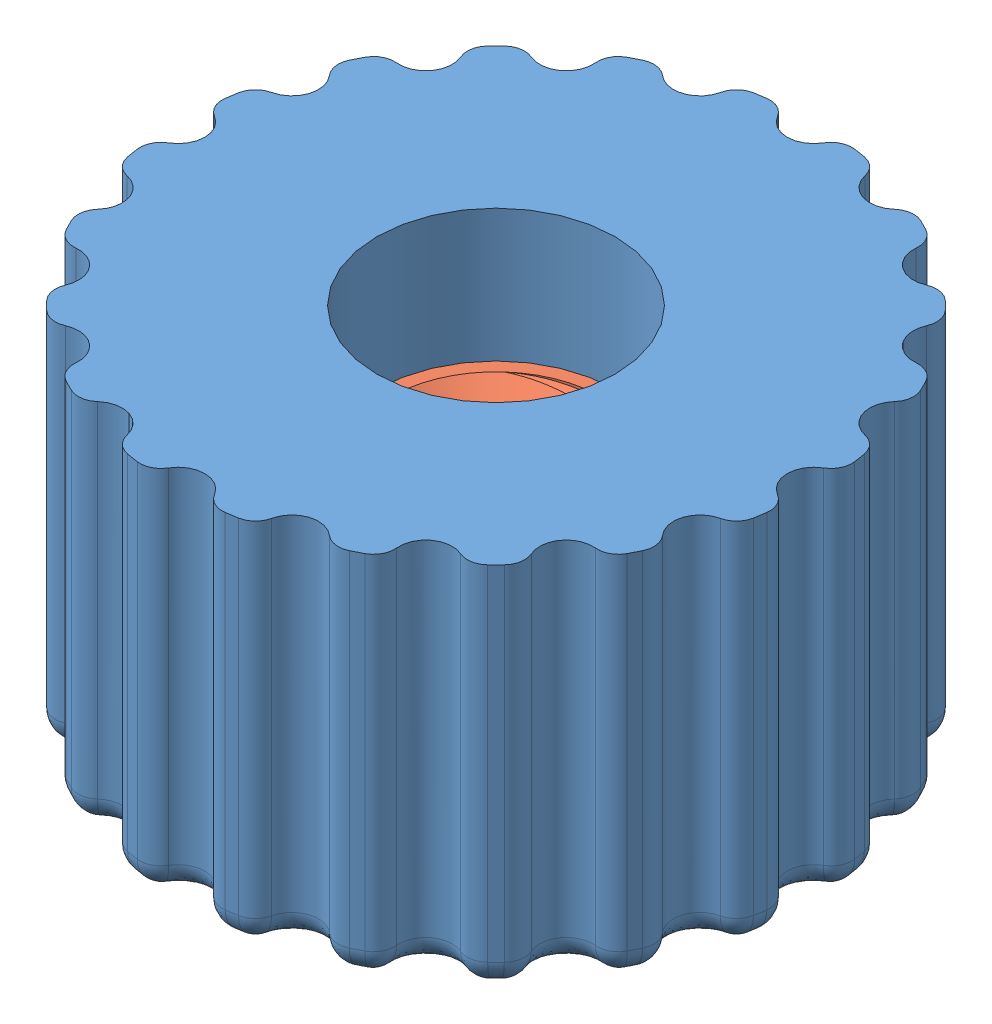
SolidWorks assembly M8_short_knob_assembly, configuration Default. Lengths in mm.
Overall size (23.87 14.07 23.87).
2 component instances, 2 part files, 3 mates.
Components (placement in the parent):
- knob^M8_short_knob_assembly-1: knob^M8_short_knob_assembly [Default] at origin size (23.87 14.07 23.87) (virtual)
- M8 x 1.25 Hex Nut-1: M8 x 1.25 Hex Nut [90592A022] at (0 5.75 0) x (-0.866025 0 -0.5) z (-0.5 0 0.866025) size (13 7.48 15.01)
Mates (geometry in assembly coordinates):
- Concentric1: concentric anti-aligned: circle of knob^M8_short_knob_assembly-1; circle of M8 x 1.25 Hex Nut-1
- Parallel1: parallel anti-aligned: plane of knob^M8_short_knob_assembly-1 through (-7.621 9 0) normal (0.866025 0 0.5); plane of M8 x 1.25 Hex Nut-1 through (-7.5056 2.5 0) normal (-0.866025 0 -0.5)
- Coincident2: coincident anti-aligned: plane of knob^M8_short_knob_assembly-1 through (0 9 0) normal (0 -1 0); plane of M8 x 1.25 Hex Nut-1 through (7.5056 9 0) normal (0 1 0)
